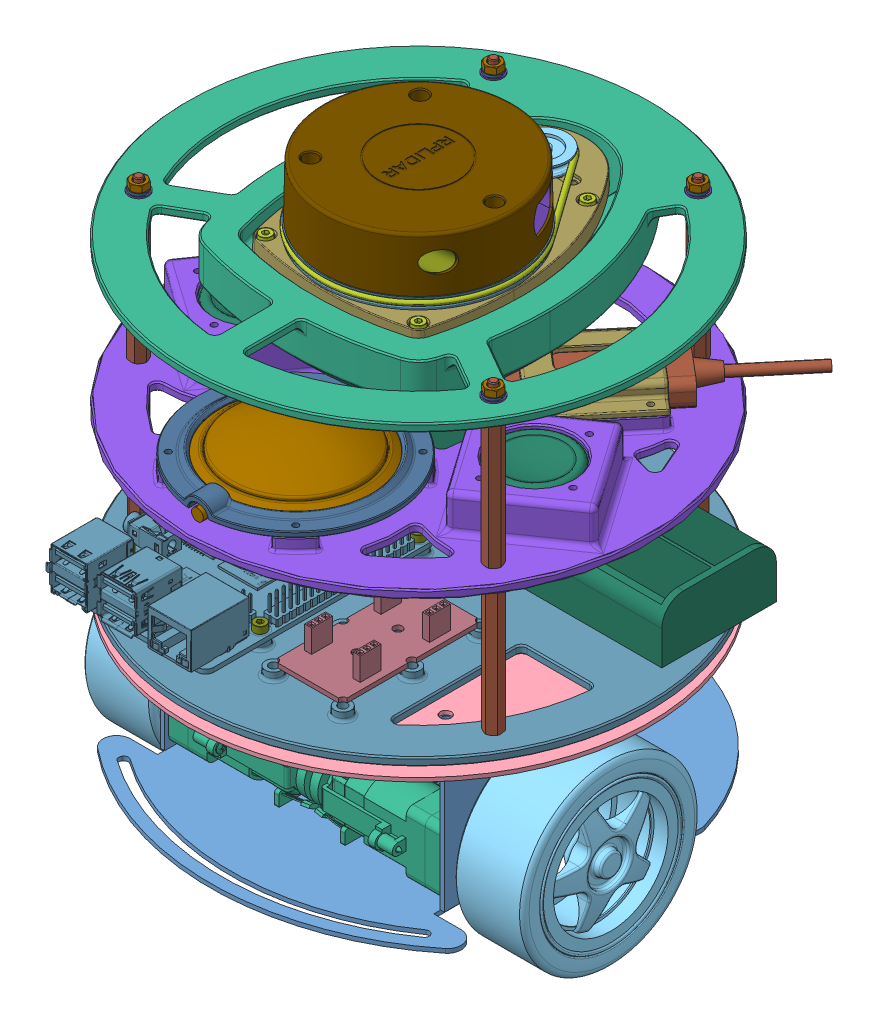
SolidWorks assembly ABOT_V2, configuration По умолчанию. Lengths in mm.
Overall size (170 211.91 174.34).
151 component instances, 52 part files, 151 mates.
Components (placement in the parent):
- LOWER_PLATE-1: LOWER_PLATE [По умолчанию] at origin size (144.85 55.5 162.2)
- CASTER_WHEEL_CASE-1: CASTER_WHEEL_CASE [Default] at (0 -11 -78) size (48.4 16.5 32.2)
- CASTER_WHEEL_BALL-1: CASTER_WHEEL_BALL [Default] at (0 -11 -78) size (14 14 14)
- UPPER_PLATE-1: UPPER_PLATE [Default] at (0 55.5 -10) x (0 0 -1) z (0 1 0) size (169.5 169.5 1.4)
- WHEEL_D65_W26-1: WHEEL_D65_W26 [Predeterminado] at (68 14.5 0) x (1 0 0) z (0 -1 0) size (29 65 65)
- WHEEL_D65_W26-2: WHEEL_D65_W26 [Predeterminado] at (-68 14.5 0) x (-1 0 0) z (0 1 0) size (29 65 65)
- TT_ANGLE_MOTOR_WITH_ENCODER-3: TT_ANGLE_MOTOR_WITH_ENCODER [По умолчанию] at (43.5 16.5594 11.0834) x (0 0 -1) z (-1 0 0) size (47.9 25.5 58.37)
- TT_ANGLE_MOTOR_WITH_ENCODER-4: TT_ANGLE_MOTOR_WITH_ENCODER [По умолчанию] at (-43.5 12.4406 11.0834) x (0 0 -1) z (1 0 0) size (47.9 25.5 58.37)
- SCREWS_ASSM_1-1: SCREWS_ASSM_1 [По умолчанию] at (64.9952 52 27.525) x (-0.813242 0 0.581925) z (-0.581925 0 -0.813242) size (7.78 19 7.78)
  - DIN_912_M3_16H-1: DIN_912_M3_16H [По умолчанию] x (0 1 0) z (0.698971 0 0.71515) size (19 5.5 5.5)
  - DIN_125_M3_WASHER_NORMAL-3: DIN_125_M3_WASHER_NORMAL [Default] at (0 3.5 0) x (0 0 1) z (0 -1 0) size (7 7 0.5)
  - DIN_934_M3_HEX_NUT-1: DIN_934_M3_HEX_NUT [По умолчанию] at (0 8.6 0) x (-0.959906 0 0.280322) z (0 -1 0) size (5.5 6.35 2.4)
  - DIN_125_M3_WASHER_NORMAL-2: DIN_125_M3_WASHER_NORMAL [Default] at (0 5.4 0) x (1 0 0) z (0 -1 0) size (7 7 0.5)
  - DIN_127_M3_SPRING_WASHER-1: DIN_127_M3_SPRING_WASHER [Default] at (0 6.2 0) x (1 0 0) z (0 -1 0) size (6.19 6.2 0.8)
- SCREWS_ASSM_1-2: SCREWS_ASSM_1 [По умолчанию] at (37.525 52 -74.9952) x (-0.954973 0 -0.296694) z (0.296694 0 -0.954973) size (7.78 19 7.78)
  - DIN_912_M3_16H-1: DIN_912_M3_16H [По умолчанию] x (0 1 0) z (0.698971 0 0.71515) size (19 5.5 5.5)
  - DIN_125_M3_WASHER_NORMAL-3: DIN_125_M3_WASHER_NORMAL [Default] at (0 3.5 0) x (0 0 1) z (0 -1 0) size (7 7 0.5)
  - DIN_934_M3_HEX_NUT-1: DIN_934_M3_HEX_NUT [По умолчанию] at (0 8.6 0) x (-0.959906 0 0.280322) z (0 -1 0) size (5.5 6.35 2.4)
  - DIN_125_M3_WASHER_NORMAL-2: DIN_125_M3_WASHER_NORMAL [Default] at (0 5.4 0) x (1 0 0) z (0 -1 0) size (7 7 0.5)
  - DIN_127_M3_SPRING_WASHER-1: DIN_127_M3_SPRING_WASHER [Default] at (0 6.2 0) x (1 0 0) z (0 -1 0) size (6.19 6.2 0.8)
- SCREWS_ASSM_1-3: SCREWS_ASSM_1 [По умолчанию] at (-37.525 52 -74.9952) size (7.78 19 7.78)
  - DIN_912_M3_16H-1: DIN_912_M3_16H [По умолчанию] x (0 1 0) z (0.698971 0 0.71515) size (19 5.5 5.5)
  - DIN_125_M3_WASHER_NORMAL-3: DIN_125_M3_WASHER_NORMAL [Default] at (0 3.5 0) x (0 0 1) z (0 -1 0) size (7 7 0.5)
  - DIN_934_M3_HEX_NUT-1: DIN_934_M3_HEX_NUT [По умолчанию] at (0 8.6 0) x (-0.959906 0 0.280322) z (0 -1 0) size (5.5 6.35 2.4)
  - DIN_125_M3_WASHER_NORMAL-2: DIN_125_M3_WASHER_NORMAL [Default] at (0 5.4 0) x (1 0 0) z (0 -1 0) size (7 7 0.5)
  - DIN_127_M3_SPRING_WASHER-1: DIN_127_M3_SPRING_WASHER [Default] at (0 6.2 0) x (1 0 0) z (0 -1 0) size (6.19 6.2 0.8)
- SCREWS_ASSM_1-4: SCREWS_ASSM_1 [По умолчанию] at (-64.9952 52 27.525) size (7.78 19 7.78)
  - DIN_912_M3_16H-1: DIN_912_M3_16H [По умолчанию] x (0 1 0) z (0.698971 0 0.71515) size (19 5.5 5.5)
  - DIN_125_M3_WASHER_NORMAL-3: DIN_125_M3_WASHER_NORMAL [Default] at (0 3.5 0) x (0 0 1) z (0 -1 0) size (7 7 0.5)
  - DIN_934_M3_HEX_NUT-1: DIN_934_M3_HEX_NUT [По умолчанию] at (0 8.6 0) x (-0.959906 0 0.280322) z (0 -1 0) size (5.5 6.35 2.4)
  - DIN_125_M3_WASHER_NORMAL-2: DIN_125_M3_WASHER_NORMAL [Default] at (0 5.4 0) x (1 0 0) z (0 -1 0) size (7 7 0.5)
  - DIN_127_M3_SPRING_WASHER-1: DIN_127_M3_SPRING_WASHER [Default] at (0 6.2 0) x (1 0 0) z (0 -1 0) size (6.19 6.2 0.8)
- STANDOFF_M3_50-13: STANDOFF_M3_50 [По умолчанию] at (-37.525 63.4 -74.9952) x (0 1 0) z (0.899685 0 0.436539) size (58 6.35 5.5)
- STANDOFF_M3_50-10: STANDOFF_M3_50 [По умолчанию] at (-64.9952 63.4 27.525) x (0 1 0) z (-0.609784 0 0.792568) size (58 6.35 5.5)
- STANDOFF_M3_50-11: STANDOFF_M3_50 [По умолчанию] at (64.9952 63.4 27.525) x (0 1 0) z (0.551155 0 0.834403) size (58 6.35 5.5)
- STANDOFF_M3_50-12: STANDOFF_M3_50 [По умолчанию] at (37.525 63.4 -74.9952) x (0 1 0) z (-0.976661 0 -0.214789) size (58 6.35 5.5)
- LIDAR-2: LIDAR [По умолчанию] at (0 184.9 -10) x (0 0 -1) z (1 0 0) size (102.81 52.61 71.78)
  - 1-1: 1 [По умолчанию] at (0 -17 0) size (96.74 12.71 70.28)
  - 2-1: 2 [По умолчанию] at (0 -15 0) x (1 0 0) z (0 -1 0) size (47 47 7.01)
  - 3-1: 3 [По умолчанию] at (0 -13 0) x (0.00451 0 -0.99999) z (0.99999 0 0.00451) size (70.79 21.41 70.79)
  - 4-1: 4 [По умолчанию] at (-25.1552 0 -6.8741) x (0.990886 0 -0.134705) z (0.134705 0 0.990886) size (6.5 6.5 21.2)
  - 5-1: 5 [По умолчанию] at (0 -9 0) x (-0.99999 0 -0.00451) z (0.00451 0 -0.99999) size (15.26 18.52 21.56)
  - 6-1: 6 [По умолчанию] at (0 -9 0) x (-0.99999 0 -0.00451) z (0.00451 0 -0.99999) size (22.09 18.86 24.76)
  - 7-1: 7 [По умолчанию] at (0 9 0) x (0.99999 0 0.00451) z (0.00451 0 -0.99999) size (70 19.51 70)
  - 8-1: 8 [По умолчанию] at (0 -26 0) x (0.987093 0 -0.160146) z (0.160146 0 0.987093) size (25 1.2 25)
  - 9-1: 9 [По умолчанию] at (0 -27 0) size (55.5 1 57)
  - 10-1: 10 [По умолчанию] at (0 -28 0) size (59.96 11.11 60.96)
  - 11-1: 11 [По умолчанию] at (45.5 -36.5 0) x (0 0 -1) z (1 0 0) size (32 30.21 32.01)
  - 12-1: 12 [По умолчанию] at (45.5 -14.5 0) x (0.135455 0 -0.990784) z (0.990784 0 0.135455) size (18 5.5 18)
  - 13-1: 13 [По умолчанию] at (16.948 0 11.5766) x (0.136926 0.990581 0.000618) z (-0.00451 0 0.99999) size (14 14 11.5)
  - 14-1: 14 [По умолчанию] at (0 -12.5 0) x (1 0 0) z (0 -1 0) size (90.89 71.78 2)
  - 15-1: 15 [По умолчанию] at (24.11 -29.4 0) x (0 0 -1) z (0 -1 0) size (10.15 4.2 4.7)
  - 16-1: 16 [По умолчанию] at (45.5 -40.1 0) x (-0.441218 0 -0.8974) z (0.8974 0 -0.441218) size (32 1.6 32)
  - 17-1: 17 [По умолчанию] at (32.56 -41.8 0) x (0 0 1) z (0 -1 0) size (8.9 5.2 3.4)
  - 19-1: 19 [По умолчанию] at (0 -36 0) x (1 0 0) z (0 0 -1) size (80.7 4.7 70)
  - 20-1: 20 [По умолчанию] at (0 -37.6 27.1) x (0 -1 0) z (1 0 0) size (8.2 5 20)
  - 22-1: 22 [По умолчанию] at (17.68 -37.7 0) x (0 0 1) z (1 0 0) size (8.8 4.7 4.36)
- PRINT_PLATE_0-1: PRINT_PLATE_0 [Default] at (0 60.4 -10) x (0 0 -1) z (0 1 0) size (170 170 6)
- COMMON_18650_BATTERY_HOLDER_DUMMY-1: COMMON_18650_BATTERY_HOLDER_DUMMY [Default] at (38.075 63.4 -43.9612) x (0 0 -1) z (1 0 0) size (42 20.5 76.3)
- COMMON_18650_BATTERY_HOLDER_DUMMY-2: COMMON_18650_BATTERY_HOLDER_DUMMY [Default] at (-38.075 63.4 -43.9612) x (0 0 -1) z (1 0 0) size (42 20.5 76.3)
- SCREWS_ASSM_2-1: SCREWS_ASSM_2 [Default] at (-5 70.48 43) x (0 -1 0) z (-0.89919 0 0.437559) size (13.2 7.37 7.37)
  - DIN_912_M2.5_10H-1: DIN_912_M2.5_10H [По умолчанию] at origin size (12.5 4.5 4.5)
  - DIN_125_M2.5_WASHER_NORMAL-1: DIN_125_M2.5_WASHER_NORMAL [Default] at (10.6 0 0) x (0 -0.264678 0.964337) z (-1 0 0) size (6 6 0.5)
  - DIN_934_M2.5_HEX_NUT-1: DIN_934_M2.5_HEX_NUT [По умолчанию] at (13.2 0 0) x (0 0 1) z (-1 0 0) size (5 5.77 2)
  - DIN_127_M2.5_SPRING_WASHER-1: DIN_127_M2.5_SPRING_WASHER [Default] at (11.2 0 0) x (0 0 1) z (-1 0 0) size (5.09 5.1 0.6)
- SCREWS_ASSM_2-2: SCREWS_ASSM_2 [Default] at (-54 70.48 43) x (0 -1 0) z (-0.949497 0 -0.313777) size (13.2 7.37 7.37)
  - DIN_912_M2.5_10H-1: DIN_912_M2.5_10H [По умолчанию] at origin size (12.5 4.5 4.5)
  - DIN_125_M2.5_WASHER_NORMAL-1: DIN_125_M2.5_WASHER_NORMAL [Default] at (10.6 0 0) x (0 -0.264678 0.964337) z (-1 0 0) size (6 6 0.5)
  - DIN_934_M2.5_HEX_NUT-1: DIN_934_M2.5_HEX_NUT [По умолчанию] at (13.2 0 0) x (0 0 1) z (-1 0 0) size (5 5.77 2)
  - DIN_127_M2.5_SPRING_WASHER-1: DIN_127_M2.5_SPRING_WASHER [Default] at (11.2 0 0) x (0 0 1) z (-1 0 0) size (5.09 5.1 0.6)
- SCREWS_ASSM_2-3: SCREWS_ASSM_2 [Default] at (-54 70.48 -15) x (0 -1 0) z (-0.237105 0 0.971484) size (13.2 7.37 7.37)
  - DIN_912_M2.5_10H-1: DIN_912_M2.5_10H [По умолчанию] at origin size (12.5 4.5 4.5)
  - DIN_125_M2.5_WASHER_NORMAL-1: DIN_125_M2.5_WASHER_NORMAL [Default] at (10.6 0 0) x (0 -0.264678 0.964337) z (-1 0 0) size (6 6 0.5)
  - DIN_934_M2.5_HEX_NUT-1: DIN_934_M2.5_HEX_NUT [По умолчанию] at (13.2 0 0) x (0 0 1) z (-1 0 0) size (5 5.77 2)
  - DIN_127_M2.5_SPRING_WASHER-1: DIN_127_M2.5_SPRING_WASHER [Default] at (11.2 0 0) x (0 0 1) z (-1 0 0) size (5.09 5.1 0.6)
- SCREWS_ASSM_2-4: SCREWS_ASSM_2 [Default] at (-5 70.48 -15) x (0 -1 0) z (-0.388057 0 0.921636) size (13.2 7.37 7.37)
  - DIN_912_M2.5_10H-1: DIN_912_M2.5_10H [По умолчанию] at origin size (12.5 4.5 4.5)
  - DIN_125_M2.5_WASHER_NORMAL-1: DIN_125_M2.5_WASHER_NORMAL [Default] at (10.6 0 0) x (0 -0.264678 0.964337) z (-1 0 0) size (6 6 0.5)
  - DIN_934_M2.5_HEX_NUT-1: DIN_934_M2.5_HEX_NUT [По умолчанию] at (13.2 0 0) x (0 0 1) z (-1 0 0) size (5 5.77 2)
  - DIN_127_M2.5_SPRING_WASHER-1: DIN_127_M2.5_SPRING_WASHER [Default] at (11.2 0 0) x (0 0 1) z (-1 0 0) size (5.09 5.1 0.6)
- SCREWS_ASSM_3-1: SCREWS_ASSM_3 [Default] at (-38.075 66 -33.4612) x (0 -1 0) z (0 0 1) size (8 6.6 6.6)
  - DIN_125_M2_WASHER_NORMAL-1: DIN_125_M2_WASHER_NORMAL [Default] at (5.9 0 0) x (0 -0.405412 0.914134) z (-1 0 0) size (5 5 0.3)
  - DIN_127_M2_SPRING_WASHER-1: DIN_127_M2_SPRING_WASHER [Default] at (6.4 0 0) x (0 0 1) z (-1 0 0) size (4.39 4.4 0.5)
  - DIN_912_M2_6H-1: DIN_912_M2_6H [По умолчанию] at origin size (8 3.8 3.8)
  - DIN_934_M2_HEX_NUT-1: DIN_934_M2_HEX_NUT [По умолчанию] at (8 0 0) x (0 0.297102 0.954846) z (-1 0 0) size (4 4.62 1.6)
- SCREWS_ASSM_3-2: SCREWS_ASSM_3 [Default] at (38.075 66 -33.4612) x (0 -1 0) z (0 0 1) size (8 6.6 6.6)
  - DIN_125_M2_WASHER_NORMAL-1: DIN_125_M2_WASHER_NORMAL [Default] at (5.9 0 0) x (0 -0.405412 0.914134) z (-1 0 0) size (5 5 0.3)
  - DIN_127_M2_SPRING_WASHER-1: DIN_127_M2_SPRING_WASHER [Default] at (6.4 0 0) x (0 0 1) z (-1 0 0) size (4.39 4.4 0.5)
  - DIN_912_M2_6H-1: DIN_912_M2_6H [По умолчанию] at origin size (8 3.8 3.8)
  - DIN_934_M2_HEX_NUT-1: DIN_934_M2_HEX_NUT [По умолчанию] at (8 0 0) x (0 0.297102 0.954846) z (-1 0 0) size (4 4.62 1.6)
- SCREWS_ASSM_3-3: SCREWS_ASSM_3 [Default] at (38.075 66 -54.4612) x (0 -1 0) z (-0.226683 0 0.973969) size (8 6.6 6.6)
  - DIN_125_M2_WASHER_NORMAL-1: DIN_125_M2_WASHER_NORMAL [Default] at (5.9 0 0) x (0 -0.405412 0.914134) z (-1 0 0) size (5 5 0.3)
  - DIN_127_M2_SPRING_WASHER-1: DIN_127_M2_SPRING_WASHER [Default] at (6.4 0 0) x (0 0 1) z (-1 0 0) size (4.39 4.4 0.5)
  - DIN_912_M2_6H-1: DIN_912_M2_6H [По умолчанию] at origin size (8 3.8 3.8)
  - DIN_934_M2_HEX_NUT-1: DIN_934_M2_HEX_NUT [По умолчанию] at (8 0 0) x (0 0.297102 0.954846) z (-1 0 0) size (4 4.62 1.6)
- SCREWS_ASSM_3-4: SCREWS_ASSM_3 [Default] at (-38.075 66 -54.4612) x (0 -1 0) z (0 0 1) size (8 6.6 6.6)
  - DIN_125_M2_WASHER_NORMAL-1: DIN_125_M2_WASHER_NORMAL [Default] at (5.9 0 0) x (0 -0.405412 0.914134) z (-1 0 0) size (5 5 0.3)
  - DIN_127_M2_SPRING_WASHER-1: DIN_127_M2_SPRING_WASHER [Default] at (6.4 0 0) x (0 0 1) z (-1 0 0) size (4.39 4.4 0.5)
  - DIN_912_M2_6H-1: DIN_912_M2_6H [По умолчанию] at origin size (8 3.8 3.8)
  - DIN_934_M2_HEX_NUT-1: DIN_934_M2_HEX_NUT [По умолчанию] at (8 0 0) x (0 0.297102 0.954846) z (-1 0 0) size (4 4.62 1.6)
- PRINT_PLATE_1-1: PRINT_PLATE_1 [Default] at (0 166.4 -10) x (0 0 -1) z (0 1 0) size (170 170 20.5)
- SCREWS_ASSM_4-1: SCREWS_ASSM_4 [Default] at (-20 169.9 -52) x (0 -1 0) z (0.489917 0 0.871769) size (27.5 6 6)
  - DIN_912_M2.5_25H-1: DIN_912_M2.5_25H [По умолчанию] at origin size (27.5 4.5 4.5)
  - DIN_125_M2.5_WASHER_NORMAL-1: DIN_125_M2.5_WASHER_NORMAL [Default] at (23.1 0 0) x (0 0 1) z (-1 0 0) size (6 6 0.5)
  - DIN_127_M2.5_SPRING_WASHER-1: DIN_127_M2.5_SPRING_WASHER [Default] at (23.7 0 0) x (0 0 1) z (-1 0 0) size (5.09 5.1 0.6)
  - DIN_934_M2.5_HEX_NUT-1: DIN_934_M2.5_HEX_NUT [По умолчанию] at (25.7 0 0) x (0 0 1) z (-1 0 0) size (5 5.77 2)
- SCREWS_ASSM_4-2: SCREWS_ASSM_4 [Default] at (20 169.9 -52) x (0 -1 0) z (0.489917 0 0.871769) size (27.5 6 6)
  - DIN_912_M2.5_25H-1: DIN_912_M2.5_25H [По умолчанию] at origin size (27.5 4.5 4.5)
  - DIN_125_M2.5_WASHER_NORMAL-1: DIN_125_M2.5_WASHER_NORMAL [Default] at (23.1 0 0) x (0 0 1) z (-1 0 0) size (6 6 0.5)
  - DIN_127_M2.5_SPRING_WASHER-1: DIN_127_M2.5_SPRING_WASHER [Default] at (23.7 0 0) x (0 0 1) z (-1 0 0) size (5.09 5.1 0.6)
  - DIN_934_M2.5_HEX_NUT-1: DIN_934_M2.5_HEX_NUT [По умолчанию] at (25.7 0 0) x (0 0 1) z (-1 0 0) size (5 5.77 2)
- SCREWS_ASSM_4-3: SCREWS_ASSM_4 [Default] at (28 169.9 18) x (0 -1 0) z (0.489917 0 0.871769) size (27.5 6 6)
  - DIN_912_M2.5_25H-1: DIN_912_M2.5_25H [По умолчанию] at origin size (27.5 4.5 4.5)
  - DIN_125_M2.5_WASHER_NORMAL-1: DIN_125_M2.5_WASHER_NORMAL [Default] at (23.1 0 0) x (0 0 1) z (-1 0 0) size (6 6 0.5)
  - DIN_127_M2.5_SPRING_WASHER-1: DIN_127_M2.5_SPRING_WASHER [Default] at (23.7 0 0) x (0 0 1) z (-1 0 0) size (5.09 5.1 0.6)
  - DIN_934_M2.5_HEX_NUT-1: DIN_934_M2.5_HEX_NUT [По умолчанию] at (25.7 0 0) x (0 0 1) z (-1 0 0) size (5 5.77 2)
- SCREWS_ASSM_4-4: SCREWS_ASSM_4 [Default] at (-28 169.9 18) x (0 -1 0) z (0.489917 0 0.871769) size (27.5 6 6)
  - DIN_912_M2.5_25H-1: DIN_912_M2.5_25H [По умолчанию] at origin size (27.5 4.5 4.5)
  - DIN_125_M2.5_WASHER_NORMAL-1: DIN_125_M2.5_WASHER_NORMAL [Default] at (23.1 0 0) x (0 0 1) z (-1 0 0) size (6 6 0.5)
  - DIN_127_M2.5_SPRING_WASHER-1: DIN_127_M2.5_SPRING_WASHER [Default] at (23.7 0 0) x (0 0 1) z (-1 0 0) size (5.09 5.1 0.6)
  - DIN_934_M2.5_HEX_NUT-1: DIN_934_M2.5_HEX_NUT [По умолчанию] at (25.7 0 0) x (0 0 1) z (-1 0 0) size (5 5.77 2)
- SCREWS_ASSM_5-1: SCREWS_ASSM_5 [Default] at (37.525 173.1 -74.9952) x (1 0 0) z (0 -1 0) size (8.46 8.46 3.7)
  - DIN_934_M3_HEX_NUT-1: DIN_934_M3_HEX_NUT [По умолчанию] at origin size (5.5 6.35 2.4)
  - DIN_125_M3_WASHER_NORMAL-1: DIN_125_M3_WASHER_NORMAL [Default] at (0 0 3.2) x (0.971662 0.236376 0) z (0 0 1) size (7 7 0.5)
  - DIN_127_M3_SPRING_WASHER-1: DIN_127_M3_SPRING_WASHER [Default] at (0 0 2.4) size (6.19 6.2 0.8)
- SCREWS_ASSM_5-2: SCREWS_ASSM_5 [Default] at (-37.525 173.1 -74.9952) x (1 0 0) z (0 -1 0) size (8.46 8.46 3.7)
  - DIN_934_M3_HEX_NUT-1: DIN_934_M3_HEX_NUT [По умолчанию] at origin size (5.5 6.35 2.4)
  - DIN_125_M3_WASHER_NORMAL-1: DIN_125_M3_WASHER_NORMAL [Default] at (0 0 3.2) x (0.971662 0.236376 0) z (0 0 1) size (7 7 0.5)
  - DIN_127_M3_SPRING_WASHER-1: DIN_127_M3_SPRING_WASHER [Default] at (0 0 2.4) size (6.19 6.2 0.8)
- SCREWS_ASSM_5-3: SCREWS_ASSM_5 [Default] at (-64.9952 173.1 27.525) x (1 0 0) z (0 -1 0) size (8.46 8.46 3.7)
  - DIN_934_M3_HEX_NUT-1: DIN_934_M3_HEX_NUT [По умолчанию] at origin size (5.5 6.35 2.4)
  - DIN_125_M3_WASHER_NORMAL-1: DIN_125_M3_WASHER_NORMAL [Default] at (0 0 3.2) x (0.971662 0.236376 0) z (0 0 1) size (7 7 0.5)
  - DIN_127_M3_SPRING_WASHER-1: DIN_127_M3_SPRING_WASHER [Default] at (0 0 2.4) size (6.19 6.2 0.8)
- SCREWS_ASSM_5-4: SCREWS_ASSM_5 [Default] at (64.9952 173.1 27.525) x (1 0 0) z (0 -1 0) size (8.46 8.46 3.7)
  - DIN_934_M3_HEX_NUT-1: DIN_934_M3_HEX_NUT [По умолчанию] at origin size (5.5 6.35 2.4)
  - DIN_125_M3_WASHER_NORMAL-1: DIN_125_M3_WASHER_NORMAL [Default] at (0 0 3.2) x (0.971662 0.236376 0) z (0 0 1) size (7 7 0.5)
  - DIN_127_M3_SPRING_WASHER-1: DIN_127_M3_SPRING_WASHER [Default] at (0 0 2.4) size (6.19 6.2 0.8)
- PRINT_PLATE_SOUND_0-1: PRINT_PLATE_SOUND_0 [Default] at (0 113.4 -10) x (0 0 -1) z (0 1 0) size (170 170 20)
- TABLETOP_MICROPHONE_ATR4697-1: TABLETOP_MICROPHONE_ATR4697 [Default] at (0 116.4 35) x (0 0 1) z (-1 0 0) size (66 15 60)
- PRINT_MIC_CAP-1: PRINT_MIC_CAP [Default] at (0 120.9 35) size (72 5.58 72)
- CREATIVE_SOUND_BLASTER_PLAY_3-1: CREATIVE_SOUND_BLASTER_PLAY_3 [Default] at (45.895 121.1 -64.6956) x (0.642788 0 -0.766044) z (0.766044 0 0.642788) size (86.8 9.4 22)
- PRINT_SOUND_CARD_CAP-1: PRINT_SOUND_CARD_CAP [Default] at (28.9254 121.1 -44.472) x (0.642788 0 -0.766044) z (0.766044 0 0.642788) size (38 6.7 38)
- STANDOFF_M3_50-6: STANDOFF_M3_50 [По умолчанию] at (37.525 116.4 -74.9952) x (0 1 0) z (-0.819797 0 -0.572654) size (58 6.35 5.5)
- STANDOFF_M3_50-7: STANDOFF_M3_50 [По умолчанию] at (64.9952 116.4 27.525) x (0 1 0) z (0.788533 0 0.614992) size (58 6.35 5.5)
- STANDOFF_M3_50-8: STANDOFF_M3_50 [По умолчанию] at (-64.9952 116.4 27.525) x (0 1 0) z (-0.908998 0 0.416801) size (58 6.35 5.5)
- STANDOFF_M3_50-9: STANDOFF_M3_50 [По умолчанию] at (-37.525 116.4 -74.9952) x (0 1 0) z (0.784935 0 0.619578) size (58 6.35 5.5)
- TROYKA_PAD_X2_DUMMY-1: TROYKA_PAD_X2_DUMMY [Default] at (20 68 25) x (0 0 1) z (-1 0 0) size (50.8 11.6 25.4)
- RP_4_DUMMY-1: RP_4_DUMMY [Default] at (-29.5 67.19 24) x (0 0 1) z (-1 0 0) size (88.99 19.9 58.4)
- VECO_32KC08_1-1: VECO_32KC08_1 [Default] at (51.7024 127.3 -0.8835) x (0.819152 0 -0.573576) z (0.573576 0 0.819152) size (32 14.7 32)
- VECO_32KC08_1-2: VECO_32KC08_1 [Default] at (-51.7024 127.3 -0.8835) x (0.819152 0 0.573576) z (-0.573576 0 0.819152) size (32 14.7 32)
- TROYKA_AMPLIFIER_D-1: TROYKA_AMPLIFIER_D [По умолчанию] at (-46.8176 131.8525 -46.0374) x (0.642788 0 0.766044) z (0 1 0) size (25.4 25.4 18.38)
Mates (geometry in assembly coordinates):
- Концентричный17: concentric anti-aligned: cylinder of LOWER_PLATE-1 through (0 1.5 -78) axis (0 -1 0) radius 16; cylinder of CASTER_WHEEL_CASE-1 through (0 -14 -78) axis (0 1 0) radius 16.1
- Концентричный18: concentric aligned: cylinder of LOWER_PLATE-1 through (20 0 -78) axis (0 1 0) radius 2.05; cylinder of CASTER_WHEEL_CASE-1 through (20 -14 -78) axis (0 1 0) radius 2
- Совпадение15: coincident anti-aligned: plane of LOWER_PLATE-1 through (0 1.5 0) normal (0 1 0); plane of CASTER_WHEEL_CASE-1 through (0 1.5 -78) normal (0 -1 0)
- Совпадение16: coordinate: point of CASTER_WHEEL_CASE-1; point of CASTER_WHEEL_BALL-1
- Концентричный22: concentric aligned: cylinder of LOWER_PLATE-1 through (-45 55.5 25) axis (0 -1 0) radius 1.5; cylinder of UPPER_PLATE-1 through (-45 56.9 25) axis (0 -1 0) radius 2
- Концентричный23: concentric aligned: cylinder of LOWER_PLATE-1 through (45 55.5 -25) axis (0 -1 0) radius 1.5; cylinder of UPPER_PLATE-1 through (45 56.9 -25) axis (0 -1 0) radius 2
- Совпадение30: coincident anti-aligned: plane of LOWER_PLATE-1 through (0 55.5 0) normal (0 1 0); plane of UPPER_PLATE-1 through (0 55.5 -10) normal (0 -1 0)
- Совпадение35: coincident anti-aligned: plane of LOWER_PLATE-1 through (52 55 0) normal (1 0 0); plane of WHEEL_D65_W26-1 through (52 14.5 0) normal (-1 0 0)
- Совпадение36: coincident anti-aligned: plane of LOWER_PLATE-1 through (-52 55 0) normal (-1 0 0); plane of WHEEL_D65_W26-2 through (-52 14.5 0) normal (1 0 0)
- Concentric1: concentric anti-aligned: cylinder of LOWER_PLATE-1 through (54 14.5 0) axis (-1 0 0) radius 4; cylinder of TT_ANGLE_MOTOR_WITH_ENCODER-4 through (-59.3 14.5 0) axis (1 0 0) radius 2.7
- Concentric2: concentric aligned: cylinder of LOWER_PLATE-1 through (-72.4232 14.5 11.4) axis (1 0 0) radius 2; cylinder of TT_ANGLE_MOTOR_WITH_ENCODER-4 through (-52.5 14.5 11.4) axis (1 0 0) radius 2
- Coincident1: coincident anti-aligned: plane of LOWER_PLATE-1 through (-50.5 55 -32.5) normal (1 0 0); plane of TT_ANGLE_MOTOR_WITH_ENCODER-4 through (-50.5 23.5 -8.5) normal (-1 0 0)
- Concentric3: concentric aligned: cylinder of LOWER_PLATE-1 through (54 14.5 0) axis (-1 0 0) radius 4; cylinder of TT_ANGLE_MOTOR_WITH_ENCODER-3 through (59.3 14.5 0) axis (-1 0 0) radius 2.7
- Concentric4: concentric anti-aligned: cylinder of LOWER_PLATE-1 through (-72.4232 14.5 11.4) axis (1 0 0) radius 2; cylinder of TT_ANGLE_MOTOR_WITH_ENCODER-3 through (52.5 14.5 11.4) axis (-1 0 0) radius 2
- Coincident2: coincident anti-aligned: plane of LOWER_PLATE-1 through (50.5 55 -32.5) normal (-1 0 0); plane of TT_ANGLE_MOTOR_WITH_ENCODER-3 through (50.5 5.5 -8.5) normal (1 0 0)
- Concentric5: concentric anti-aligned: cylinder of WHEEL_D65_W26-2 through (-68.8553 14.5 0) axis (-1 0 0) radius 4; cylinder of TT_ANGLE_MOTOR_WITH_ENCODER-4 through (-59.3 14.5 0) axis (1 0 0) radius 2.7
- Concentric6: concentric anti-aligned: cylinder of WHEEL_D65_W26-1 through (68.8553 14.5 0) axis (1 0 0) radius 4; cylinder of TT_ANGLE_MOTOR_WITH_ENCODER-3 through (59.3 14.5 0) axis (-1 0 0) radius 2.7
- Concentric21: concentric anti-aligned: cylinder of SCREWS_ASSM_1-1/DIN_912_M3_16H-1 through (64.9952 52 27.525) axis (0 -1 0) radius 1.5; circle of UPPER_PLATE-1
- Coincident12: coincident anti-aligned: plane of UPPER_PLATE-1 through (0 55.5 -10) normal (0 -1 0); plane of SCREWS_ASSM_1-1/DIN_125_M3_WASHER_NORMAL-3 through (64.9952 55.5 27.525) normal (0 1 0)
- Concentric22: concentric anti-aligned: cylinder of SCREWS_ASSM_1-2/DIN_912_M3_16H-1 through (37.525 52 -74.9952) axis (0 -1 0) radius 1.5; circle of UPPER_PLATE-1
- Coincident14: coincident anti-aligned: plane of UPPER_PLATE-1 through (0 55.5 -10) normal (0 -1 0); plane of SCREWS_ASSM_1-2/DIN_125_M3_WASHER_NORMAL-3 through (37.525 55.5 -74.9952) normal (0 1 0)
- Concentric23: concentric anti-aligned: circle of UPPER_PLATE-1; cylinder of SCREWS_ASSM_1-4/DIN_912_M3_16H-1 through (-64.9952 52 27.525) axis (0 -1 0) radius 1.5
- Concentric24: concentric anti-aligned: cylinder of SCREWS_ASSM_1-3/DIN_912_M3_16H-1 through (-37.525 52 -74.9952) axis (0 -1 0) radius 1.5; circle of UPPER_PLATE-1
- Coincident15: coincident anti-aligned: plane of UPPER_PLATE-1 through (0 55.5 -10) normal (0 -1 0); plane of SCREWS_ASSM_1-3/DIN_125_M3_WASHER_NORMAL-3 through (-37.525 55.5 -74.9952) normal (0 1 0)
- Coincident16: coincident anti-aligned: plane of UPPER_PLATE-1 through (0 55.5 -10) normal (0 -1 0); plane of SCREWS_ASSM_1-4/DIN_125_M3_WASHER_NORMAL-3 through (-64.9952 55.5 27.525) normal (0 1 0)
- Concentric34: concentric aligned: cylinder of ? through (-64.9952 136.4 27.525) axis (0 -1 0) radius 1.5; cylinder of ? through (-64.9952 119.4 27.525) axis (0 -1 0) radius 1.6
- Coincident26: coincident anti-aligned: plane of ? through (0 119.4 -10) normal (0 1 0); plane of LIDAR-2/1-1 through (62.2833 119.4 -10) normal (0 -1 0)
- Concentric35: concentric aligned: cylinder of ? through (20 119.4 -52) axis (0 -1 0) radius 1.5; cylinder of LIDAR-2/1-1 through (20 122.7 -52) axis (0 -1 0) radius 1.5
- Concentric36: concentric aligned: cylinder of ? through (28 119.4 18) axis (0 -1 0) radius 1.5; cylinder of LIDAR-2/1-1 through (28 122.7 18) axis (0 -1 0) radius 1.5
- Concentric38: concentric aligned: cylinder of ? through (0 -4.1 84.5) axis (0 0 -1) radius 1.6; cylinder of ? through (0 -4.1 80) axis (0 0 -1) radius 1.6
- Concentric39: concentric aligned: cylinder of ? through (0 32.9 84.5) axis (0 0 -1) radius 1.6; cylinder of ? through (0 32.9 80) axis (0 0 -1) radius 1.6
- Coincident27: coincident anti-aligned: plane of ? through (0 14.4 79.5) normal (0 0 -1); plane of ? through (0 -8.1 79.5) normal (0 0 1)
- Concentric40: concentric anti-aligned: cylinder of ? through (0 32.9 84.5) axis (0 0 -1) radius 1.6; cylinder of ? through (0 32.9 84.5) axis (0 0 1) radius 1.5
- Coincident32: coincident anti-aligned: plane of ? through (0 32.9 81.5) normal (0 0 1); plane of ? through (0 32.9 81.5) normal (0 0 -1)
- Concentric42: concentric anti-aligned: cylinder of ? through (0 -4.1 84.5) axis (0 0 -1) radius 1.6; cylinder of ? through (0 -4.1 84.5) axis (0 0 1) radius 1.5
- Coincident33: coincident anti-aligned: plane of ? through (0 -4.1 81.5) normal (0 0 1); plane of ? through (0 -4.1 81.5) normal (0 0 -1)
- Concentric43: concentric aligned: cylinder of ? through (0 -4.1 74.6) axis (0 0 1) radius 1.5; cylinder of ? through (0 -4.1 84.5) axis (0 0 1) radius 1.5
- Concentric44: concentric aligned: cylinder of ? through (0 32.9 84.5) axis (0 0 1) radius 1.5; cylinder of ? through (0 32.9 74.6) axis (0 0 1) radius 1.5
- Tangent1: tangent aligned: cylinder of ? through (0 -8.1 -10) axis (0 1 0) radius 87; plane of ? through (0 32.9 77) normal (0 0 1)
- Tangent2: tangent aligned: cylinder of ? through (0 -8.1 -10) axis (0 1 0) radius 87; plane of ? through (0 -4.1 77) normal (0 0 1)
- Концентричный24: concentric aligned: cylinder of UPPER_PLATE-1 through (0 56.9 -10) axis (0 -1 0) radius 84.75; cylinder of PRINT_PLATE_0-1 through (0 63.4 -10) axis (0 -1 0) radius 85
- Концентричный25: concentric anti-aligned: cylinder of PRINT_PLATE_0-1 through (-54 63.4 43) axis (0 -1 0) radius 1.6; cylinder of ? through (-54 68 43) axis (0 1 0) radius 1.35
- Концентричный26: concentric anti-aligned: cylinder of PRINT_PLATE_0-1 through (-5 63.4 -15) axis (0 -1 0) radius 1.6; cylinder of ? through (-5 68 -15) axis (0 1 0) radius 1.35
- Совпадение37: coincident anti-aligned: plane of PRINT_PLATE_0-1 through (0 66.4 -10) normal (0 1 0); plane of ? through (-29.5 66.4 24) normal (0 -1 0)
- Концентричный28: concentric aligned: cylinder of SCREWS_ASSM_1-1/DIN_912_M3_16H-1 through (64.9952 52 27.525) axis (0 -1 0) radius 1.5; cylinder of PRINT_PLATE_0-1 through (64.9952 63.4 27.525) axis (0 -1 0) radius 1.6
- Концентричный29: concentric anti-aligned: cylinder of UPPER_PLATE-1 through (0 56.9 -10) axis (0 -1 0) radius 84.75; cylinder of ? through (0 60.4 -10) axis (0 1 0) radius 90
- Совпадение38: coincident anti-aligned: plane of STANDOFF_M3_50-10 through (-64.9952 63.4 27.525) normal (0 -1 0); plane of PRINT_PLATE_0-1 through (0 63.4 -10) normal (0 1 0)
- Совпадение39: coincident anti-aligned: plane of STANDOFF_M3_50-12 through (37.525 63.4 -74.9952) normal (0 -1 0); plane of PRINT_PLATE_0-1 through (0 63.4 -10) normal (0 1 0)
- Совпадение40: coincident anti-aligned: plane of STANDOFF_M3_50-13 through (-37.525 63.4 -74.9952) normal (0 -1 0); plane of PRINT_PLATE_0-1 through (0 63.4 -10) normal (0 1 0)
- Концентричный30: concentric anti-aligned: cylinder of SCREWS_ASSM_1-1/DIN_912_M3_16H-1 through (64.9952 51.9 27.525) axis (0 -1 0) radius 1.5; cylinder of ? through (64.9952 60.4 27.525) axis (0 1 0) radius 1.6
- Расстояние1: distance = 3.5 mm anti-aligned: plane of UPPER_PLATE-1 through (0 56.9 -10) normal (0 1 0); plane of ? through (0 60.4 -10) normal (0 -1 0)
- Совпадение42: coincident anti-aligned: plane of STANDOFF_M3_50-11 through (64.9952 63.4 27.525) normal (0 -1 0); plane of PRINT_PLATE_0-1 through (0 63.4 -10) normal (0 1 0)
- Совпадение43: coincident anti-aligned: plane of ? through (0 63.4 -10) normal (0 1 0); plane of PRINT_PLATE_0-1 through (0 63.4 -10) normal (0 -1 0)
- Концентричный31: concentric aligned: cylinder of PRINT_PLATE_0-1 through (-38.075 63.4 -54.4612) axis (0 -1 0) radius 1.5; cylinder of COMMON_18650_BATTERY_HOLDER_DUMMY-2 through (-38.075 83.9 -54.4612) axis (0 -1 0) radius 1.5
- Концентричный32: concentric aligned: cylinder of PRINT_PLATE_0-1 through (38.075 63.4 -54.4612) axis (0 -1 0) radius 1.5; cylinder of COMMON_18650_BATTERY_HOLDER_DUMMY-1 through (38.075 83.9 -54.4612) axis (0 -1 0) radius 1.5
- Концентричный33: concentric aligned: cylinder of PRINT_PLATE_0-1 through (38.075 63.4 -33.4612) axis (0 -1 0) radius 1.5; cylinder of COMMON_18650_BATTERY_HOLDER_DUMMY-1 through (38.075 83.9 -33.4612) axis (0 -1 0) radius 1.5
- Концентричный34: concentric aligned: cylinder of PRINT_PLATE_0-1 through (-38.075 63.4 -33.4612) axis (0 -1 0) radius 1.5; cylinder of COMMON_18650_BATTERY_HOLDER_DUMMY-2 through (-38.075 83.9 -33.4612) axis (0 -1 0) radius 1.5
- Совпадение44: coincident anti-aligned: plane of PRINT_PLATE_0-1 through (0 63.4 -10) normal (0 1 0); plane of COMMON_18650_BATTERY_HOLDER_DUMMY-1 through (38.075 63.4 -43.9612) normal (0 -1 0)
- Совпадение45: coincident anti-aligned: plane of PRINT_PLATE_0-1 through (0 63.4 -10) normal (0 1 0); plane of COMMON_18650_BATTERY_HOLDER_DUMMY-2 through (-38.075 63.4 -43.9612) normal (0 -1 0)
- Концентричный35: concentric anti-aligned: cylinder of PRINT_PLATE_0-1 through (20 63.4 17.5) axis (0 -1 0) radius 1.6; cylinder of TROYKA_PAD_X2_DUMMY-1 through (20 64.8 17.5) axis (0 1 0) radius 1.6
- Концентричный36: concentric anti-aligned: cylinder of PRINT_PLATE_0-1 through (20 63.4 32.5) axis (0 -1 0) radius 1.6; cylinder of TROYKA_PAD_X2_DUMMY-1 through (20 64.8 32.5) axis (0 1 0) radius 1.6
- Совпадение46: coincident anti-aligned: plane of PRINT_PLATE_0-1 through (0 66.4 -10) normal (0 1 0); plane of TROYKA_PAD_X2_DUMMY-1 through (20 66.4 25) normal (0 -1 0)
- Distance1: distance = 3.5 mm anti-aligned: plane of UPPER_PLATE-1 through (0 56.9 -10) normal (0 1 0); plane of PRINT_PLATE_0-1 through (0 60.4 -10) normal (0 -1 0)
- Concentric45: concentric aligned: cylinder of ? through (-5 68 43) axis (0 1 0) radius 1.35; cylinder of SCREWS_ASSM_2-1/DIN_912_M2.5_10H-1 through (-5 70.49 43) axis (0 1 0) radius 1.25
- Concentric46: concentric aligned: cylinder of ? through (-54 68 43) axis (0 1 0) radius 1.35; cylinder of SCREWS_ASSM_2-2/DIN_912_M2.5_10H-1 through (-54 70.49 43) axis (0 1 0) radius 1.25
- Concentric47: concentric aligned: cylinder of ? through (-54 68 -15) axis (0 1 0) radius 1.35; cylinder of SCREWS_ASSM_2-3/DIN_912_M2.5_10H-1 through (-54 70.5 -15) axis (0 1 0) radius 1.25
- Concentric48: concentric aligned: cylinder of ? through (-5 68 -15) axis (0 1 0) radius 1.35; cylinder of SCREWS_ASSM_2-4/DIN_912_M2.5_10H-1 through (-5 70.49 -15) axis (0 1 0) radius 1.25
- Coincident35: coincident anti-aligned: plane of ? through (-5 67.99 -15) normal (0 1 0); plane of SCREWS_ASSM_2-4/DIN_912_M2.5_10H-1 through (-5 67.99 -15) normal (0 -1 0)
- Coincident36: coincident aligned: plane of ? through (-5 67.99 43) normal (0 1 0); circle of SCREWS_ASSM_2-1/DIN_912_M2.5_10H-1
- Concentric49: concentric aligned: cylinder of ? through (-54 68 43) axis (0 1 0) radius 1.35; cylinder of SCREWS_ASSM_2-2/DIN_912_M2.5_10H-1 through (-54 70.49 43) axis (0 1 0) radius 1.25
- Coincident37: coincident anti-aligned: plane of ? through (-54 67.99 43) normal (0 1 0); plane of SCREWS_ASSM_2-2/DIN_912_M2.5_10H-1 through (-54 67.99 43) normal (0 -1 0)
- Concentric50: concentric aligned: cylinder of ? through (-54 68 -15) axis (0 1 0) radius 1.35; cylinder of SCREWS_ASSM_2-3/DIN_912_M2.5_10H-1 through (-54 70.5 -15) axis (0 1 0) radius 1.25
- Coincident38: coincident anti-aligned: plane of ? through (-29.5 68 24) normal (0 1 0); plane of SCREWS_ASSM_2-3/DIN_912_M2.5_10H-1 through (-54 68 -15) normal (0 -1 0)
- Concentric51: concentric anti-aligned: cylinder of PRINT_PLATE_0-1 through (-38.075 63.4 -33.4612) axis (0 -1 0) radius 1.5; cylinder of SCREWS_ASSM_3-1/DIN_912_M2_6H-1 through (-38.075 66 -33.4612) axis (0 1 0) radius 1
- Concentric52: concentric anti-aligned: cylinder of PRINT_PLATE_0-1 through (-38.075 63.4 -54.4612) axis (0 -1 0) radius 1.5; cylinder of SCREWS_ASSM_3-4/DIN_912_M2_6H-1 through (-38.075 66 -54.4612) axis (0 1 0) radius 1
- Concentric53: concentric anti-aligned: cylinder of PRINT_PLATE_0-1 through (38.075 63.4 -33.4612) axis (0 -1 0) radius 1.5; cylinder of SCREWS_ASSM_3-2/DIN_912_M2_6H-1 through (38.075 66 -33.4612) axis (0 1 0) radius 1
- Concentric54: concentric anti-aligned: cylinder of PRINT_PLATE_0-1 through (38.075 63.4 -54.4612) axis (0 -1 0) radius 1.5; cylinder of SCREWS_ASSM_3-3/DIN_912_M2_6H-1 through (38.075 66 -54.4612) axis (0 1 0) radius 1
- Coincident39: coincident anti-aligned: plane of PRINT_PLATE_0-1 through (0 60.4 -10) normal (0 -1 0); plane of SCREWS_ASSM_3-3/DIN_125_M2_WASHER_NORMAL-1 through (38.075 60.4 -54.4612) normal (0 1 0)
- Coincident40: coincident anti-aligned: plane of PRINT_PLATE_0-1 through (0 60.4 -10) normal (0 -1 0); plane of SCREWS_ASSM_3-4/DIN_125_M2_WASHER_NORMAL-1 through (-38.075 60.4 -54.4612) normal (0 1 0)
- Coincident41: coincident anti-aligned: plane of PRINT_PLATE_0-1 through (0 60.4 -10) normal (0 -1 0); plane of SCREWS_ASSM_3-2/DIN_125_M2_WASHER_NORMAL-1 through (38.075 60.4 -33.4612) normal (0 1 0)
- Coincident42: coincident anti-aligned: plane of PRINT_PLATE_0-1 through (0 60.4 -10) normal (0 -1 0); plane of SCREWS_ASSM_3-1/DIN_125_M2_WASHER_NORMAL-1 through (-38.075 60.4 -33.4612) normal (0 1 0)
- Concentric57: concentric aligned: cylinder of LIDAR-2/1-1 through (28 167.2 18) axis (0 -1 0) radius 1.5; cylinder of PRINT_PLATE_1-1 through (28 148.9 18) axis (0 -1 0) radius 1.25
- Concentric58: concentric aligned: cylinder of LIDAR-2/1-1 through (20 167.2 -52) axis (0 -1 0) radius 1.5; cylinder of PRINT_PLATE_1-1 through (20 148.9 -52) axis (0 -1 0) radius 1.25
- Coincident45: coincident anti-aligned: plane of LIDAR-2/1-1 through (62.2833 163.9 -10) normal (0 -1 0); plane of PRINT_PLATE_1-1 through (0 163.9 -10) normal (0 1 0)
- Concentric59: concentric anti-aligned: cylinder of LIDAR-2/1-1 through (-20 167.2 -52) axis (0 -1 0) radius 1.5; cylinder of SCREWS_ASSM_4-1/DIN_912_M2.5_25H-1 through (-20 169.9 -52) axis (0 1 0) radius 1.25
- Coincident46: coincident anti-aligned: plane of LIDAR-2/1-1 through (-20 167.4 -52) normal (0 1 0); plane of SCREWS_ASSM_4-1/DIN_912_M2.5_25H-1 through (-20 167.4 -52) normal (0 -1 0)
- Concentric60: concentric anti-aligned: cylinder of LIDAR-2/1-1 through (-28 167.2 18) axis (0 -1 0) radius 1.5; cylinder of SCREWS_ASSM_4-4/DIN_912_M2.5_25H-1 through (-28 169.9 18) axis (0 1 0) radius 1.25
- Concentric61: concentric anti-aligned: cylinder of LIDAR-2/1-1 through (28 167.2 18) axis (0 -1 0) radius 1.5; cylinder of SCREWS_ASSM_4-3/DIN_912_M2.5_25H-1 through (28 169.9 18) axis (0 1 0) radius 1.25
- Concentric62: concentric anti-aligned: cylinder of LIDAR-2/1-1 through (20 167.2 -52) axis (0 -1 0) radius 1.5; cylinder of SCREWS_ASSM_4-2/DIN_912_M2.5_25H-1 through (20 169.9 -52) axis (0 1 0) radius 1.25
- Coincident47: coincident anti-aligned: plane of LIDAR-2/1-1 through (0 167.4 -10) normal (0 1 0); plane of SCREWS_ASSM_4-2/DIN_912_M2.5_25H-1 through (20 167.4 -52) normal (0 -1 0)
- Coincident48: coincident anti-aligned: plane of LIDAR-2/1-1 through (28 167.4 18) normal (0 1 0); plane of SCREWS_ASSM_4-3/DIN_912_M2.5_25H-1 through (28 167.4 18) normal (0 -1 0)
- Coincident49: coincident anti-aligned: plane of LIDAR-2/1-1 through (-28 167.4 18) normal (0 1 0); plane of SCREWS_ASSM_4-4/DIN_912_M2.5_25H-1 through (-28 167.4 18) normal (0 -1 0)
- Coincident50: coincident anti-aligned: plane of PRINT_PLATE_1-1 through (0 169.4 -10) normal (0 1 0); plane of SCREWS_ASSM_5-1/DIN_125_M3_WASHER_NORMAL-1 through (37.525 169.4 -74.9952) normal (0 -1 0)
- Coincident51: coincident anti-aligned: plane of PRINT_PLATE_1-1 through (0 169.4 -10) normal (0 1 0); plane of SCREWS_ASSM_5-2/DIN_125_M3_WASHER_NORMAL-1 through (-37.525 169.4 -74.9952) normal (0 -1 0)
- Coincident52: coincident anti-aligned: plane of PRINT_PLATE_1-1 through (0 169.4 -10) normal (0 1 0); plane of SCREWS_ASSM_5-3/DIN_125_M3_WASHER_NORMAL-1 through (-64.9952 169.4 27.525) normal (0 -1 0)
- Coincident53: coincident anti-aligned: plane of PRINT_PLATE_1-1 through (0 169.4 -10) normal (0 1 0); plane of SCREWS_ASSM_5-4/DIN_125_M3_WASHER_NORMAL-1 through (64.9952 169.4 27.525) normal (0 -1 0)
- Концентричный37: concentric aligned: cylinder of SCREWS_ASSM_1-1/DIN_912_M3_16H-1 through (64.9952 52 27.525) axis (0 -1 0) radius 1.5; cylinder of STANDOFF_M3_50-11 through (64.9952 73.4 27.525) axis (0 -1 0) radius 1.5
- Концентричный38: concentric aligned: cylinder of SCREWS_ASSM_1-2/DIN_912_M3_16H-1 through (37.525 52 -74.9952) axis (0 -1 0) radius 1.5; cylinder of STANDOFF_M3_50-12 through (37.525 73.4 -74.9952) axis (0 -1 0) radius 1.5
- Концентричный39: concentric aligned: cylinder of SCREWS_ASSM_1-3/DIN_912_M3_16H-1 through (-37.525 52 -74.9952) axis (0 -1 0) radius 1.5; cylinder of STANDOFF_M3_50-13 through (-37.525 73.4 -74.9952) axis (0 -1 0) radius 1.5
- Концентричный40: concentric aligned: cylinder of SCREWS_ASSM_1-4/DIN_912_M3_16H-1 through (-64.9952 52 27.525) axis (0 -1 0) radius 1.5; cylinder of STANDOFF_M3_50-10 through (-64.9952 73.4 27.525) axis (0 -1 0) radius 1.5
- Концентричный41: concentric aligned: cylinder of PRINT_PLATE_0-1 through (0 63.4 -10) axis (0 -1 0) radius 85; cylinder of PRINT_PLATE_SOUND_0-1 through (0 116.4 -10) axis (0 -1 0) radius 85
- Концентричный46: concentric aligned: cylinder of PRINT_PLATE_SOUND_0-1 through (0 113.4 35) axis (0 -1 0) radius 16.5; cylinder of TABLETOP_MICROPHONE_ATR4697-1 through (0 119.7 35) axis (0 -1 0) radius 26.5
- Совпадение49: coincident anti-aligned: plane of PRINT_PLATE_SOUND_0-1 through (0 116.4 -10) normal (0 1 0); plane of TABLETOP_MICROPHONE_ATR4697-1 through (0 116.4 35) normal (0 -1 0)
- Концентричный47: concentric aligned: cylinder of PRINT_PLATE_SOUND_0-1 through (23.3345 120.9 58.3345) axis (0 -1 0) radius 1.1; cylinder of PRINT_MIC_CAP-1 through (23.3345 126.4211 58.3345) axis (0 -1 0) radius 1.1
- Концентричный48: concentric aligned: cylinder of PRINT_PLATE_SOUND_0-1 through (0 113.4 35) axis (0 -1 0) radius 36; cylinder of PRINT_MIC_CAP-1 through (0 120.9 35) axis (0 -1 0) radius 36
- Совпадение50: coincident anti-aligned: plane of PRINT_PLATE_SOUND_0-1 through (-26.0653 120.9 16.7489) normal (0 1 0); plane of PRINT_MIC_CAP-1 through (0 120.9 35) normal (0 -1 0)
- Совпадение51: coincident anti-aligned: plane of PRINT_PLATE_SOUND_0-1 through (0 116.4 -10) normal (0 1 0); plane of CREATIVE_SOUND_BLASTER_PLAY_3-1 through (4.8149 116.4 -32.8512) normal (0 -1 0)
- Расстояние2: distance = 0.2 mm anti-aligned: plane of CREATIVE_SOUND_BLASTER_PLAY_3-1 through (21.6679 116.4 -18.7099) normal (0.766044 0 0.642788); plane of PRINT_PLATE_SOUND_0-1 through (49.7181 113.4 -51.8276) normal (-0.766044 0 -0.642788)
- Расстояние3: distance = 5.4 mm aligned: plane of PRINT_PLATE_SOUND_0-1 through (16.7125 113.4 -29.9172) normal (-0.642788 0 0.766044); plane of CREATIVE_SOUND_BLASTER_PLAY_3-1 through (13.2414 121.1 -25.7805) normal (-0.642788 0 0.766044)
- Концентричный49: concentric aligned: cylinder of PRINT_PLATE_SOUND_0-1 through (32.1831 121.1 -23.4628) axis (0 -1 0) radius 1.1; cylinder of PRINT_SOUND_CARD_CAP-1 through (32.1831 127.8 -23.4628) axis (0 -1 0) radius 1.1
- Концентричный50: concentric aligned: cylinder of PRINT_PLATE_SOUND_0-1 through (25.6678 121.1 -65.4812) axis (0 -1 0) radius 1.1; cylinder of PRINT_SOUND_CARD_CAP-1 through (25.6678 127.8 -65.4812) axis (0 -1 0) radius 1.1
- Совпадение54: coincident anti-aligned: plane of PRINT_PLATE_SOUND_0-1 through (41.1384 121.1 -59.0268) normal (0 1 0); plane of PRINT_SOUND_CARD_CAP-1 through (41.1384 121.1 -59.0268) normal (0 -1 0)
- Концентричный51: concentric aligned: cylinder of PRINT_PLATE_SOUND_0-1 through (64.9952 123.4 27.525) axis (0 -1 0) radius 1.6; cylinder of STANDOFF_M3_50-11 through (64.9952 121.4 27.525) axis (0 -1 0) radius 1.5
- Совпадение55: coincident anti-aligned: plane of STANDOFF_M3_50-11 through (64.9952 113.4 27.525) normal (0 1 0); plane of PRINT_PLATE_SOUND_0-1 through (0 113.4 -10) normal (0 -1 0)
- Концентричный52: concentric aligned: cylinder of STANDOFF_M3_50-10 through (-64.9952 121.4 27.525) axis (0 -1 0) radius 1.5; cylinder of STANDOFF_M3_50-8 through (-64.9952 126.4 27.525) axis (0 -1 0) radius 1.5
- Концентричный53: concentric aligned: cylinder of STANDOFF_M3_50-12 through (37.525 121.4 -74.9952) axis (0 -1 0) radius 1.5; cylinder of STANDOFF_M3_50-6 through (37.525 126.4 -74.9952) axis (0 -1 0) radius 1.5
- Концентричный54: concentric aligned: cylinder of STANDOFF_M3_50-11 through (64.9952 121.4 27.525) axis (0 -1 0) radius 1.5; cylinder of STANDOFF_M3_50-7 through (64.9952 126.4 27.525) axis (0 -1 0) radius 1.5
- Концентричный55: concentric aligned: cylinder of STANDOFF_M3_50-13 through (-37.525 121.4 -74.9952) axis (0 -1 0) radius 1.5; cylinder of STANDOFF_M3_50-9 through (-37.525 126.4 -74.9952) axis (0 -1 0) radius 1.5
- Совпадение56: coincident anti-aligned: plane of PRINT_PLATE_SOUND_0-1 through (0 116.4 -10) normal (0 1 0); plane of STANDOFF_M3_50-6 through (37.525 116.4 -74.9952) normal (0 -1 0)
- Совпадение57: coincident anti-aligned: plane of PRINT_PLATE_SOUND_0-1 through (0 116.4 -10) normal (0 1 0); plane of STANDOFF_M3_50-7 through (64.9952 116.4 27.525) normal (0 -1 0)
- Совпадение58: coincident anti-aligned: plane of PRINT_PLATE_SOUND_0-1 through (0 116.4 -10) normal (0 1 0); plane of STANDOFF_M3_50-8 through (-64.9952 116.4 27.525) normal (0 -1 0)
- Совпадение59: coincident anti-aligned: plane of PRINT_PLATE_SOUND_0-1 through (0 116.4 -10) normal (0 1 0); plane of STANDOFF_M3_50-9 through (-37.525 116.4 -74.9952) normal (0 -1 0)
- Концентричный56: concentric aligned: cylinder of PRINT_PLATE_1-1 through (64.9952 169.4 27.525) axis (0 -1 0) radius 1.6; cylinder of STANDOFF_M3_50-7 through (64.9952 174.4 27.525) axis (0 -1 0) radius 1.5
- Концентричный57: concentric aligned: cylinder of PRINT_PLATE_1-1 through (-64.9952 169.4 27.525) axis (0 -1 0) radius 1.6; cylinder of STANDOFF_M3_50-8 through (-64.9952 174.4 27.525) axis (0 -1 0) radius 1.5
- Концентричный58: concentric anti-aligned: cylinder of PRINT_PLATE_1-1 through (37.525 169.4 -74.9952) axis (0 -1 0) radius 1.6; cylinder of SCREWS_ASSM_5-1/DIN_934_M3_HEX_NUT-1 through (37.525 170.7 -74.9952) axis (0 1 0) radius 1.5
- Концентричный59: concentric anti-aligned: cylinder of PRINT_PLATE_1-1 through (64.9952 169.4 27.525) axis (0 -1 0) radius 1.6; cylinder of SCREWS_ASSM_5-4/DIN_934_M3_HEX_NUT-1 through (64.9952 170.7 27.525) axis (0 1 0) radius 1.5
- Концентричный60: concentric anti-aligned: cylinder of PRINT_PLATE_1-1 through (-64.9952 169.4 27.525) axis (0 -1 0) radius 1.6; cylinder of SCREWS_ASSM_5-3/DIN_934_M3_HEX_NUT-1 through (-64.9952 170.7 27.525) axis (0 1 0) radius 1.5
- Концентричный61: concentric anti-aligned: cylinder of PRINT_PLATE_1-1 through (-37.525 169.4 -74.9952) axis (0 -1 0) radius 1.6; cylinder of SCREWS_ASSM_5-2/DIN_934_M3_HEX_NUT-1 through (-37.525 170.7 -74.9952) axis (0 1 0) radius 1.5
- Концентричный62: concentric anti-aligned: cylinder of PRINT_PLATE_0-1 through (-5 66.4 -15) axis (0 -1 0) radius 3; cylinder of RP_4_DUMMY-1 through (-5 67.99 -15) axis (0 1 0) radius 1.35
- Концентричный63: concentric anti-aligned: cylinder of PRINT_PLATE_0-1 through (-54 66.4 43) axis (0 -1 0) radius 3; cylinder of RP_4_DUMMY-1 through (-54 67.99 43) axis (0 1 0) radius 1.35
- Совпадение60: coincident anti-aligned: plane of PRINT_PLATE_0-1 through (0 66.4 -10) normal (0 1 0); plane of RP_4_DUMMY-1 through (-54 66.4 43) normal (0 -1 0)
- Концентричный64: concentric aligned: cylinder of TABLETOP_MICROPHONE_ATR4697-1 through (0 120.9 71) axis (0 0 -1) radius 2.175; cylinder of PRINT_MIC_CAP-1 through (0 120.9 71) axis (0 0 -1) radius 3.5
- Концентричный65: concentric anti-aligned: cylinder of PRINT_PLATE_SOUND_0-1 through (51.7024 129.4 -0.8835) axis (0 -1 0) radius 14.25; cylinder of VECO_32KC08_1-1 through (51.7024 114.4 -0.8835) axis (0 1 0) radius 12.85
- Концентричный66: concentric anti-aligned: cylinder of PRINT_PLATE_SOUND_0-1 through (54.7107 129.4 -17.9444) axis (0 -1 0) radius 1.1; cylinder of VECO_32KC08_1-1 through (54.7107 114.4 -17.9444) axis (0 1 0) radius 1.15
- Совпадение61: coincident anti-aligned: plane of PRINT_PLATE_SOUND_0-1 through (0 127.4 -10) normal (0 -1 0); plane of VECO_32KC08_1-1 through (51.7024 127.4 -0.8835) normal (0 1 0)
- Концентричный67: concentric anti-aligned: cylinder of PRINT_PLATE_SOUND_0-1 through (-51.7024 129.4 -0.8835) axis (0 -1 0) radius 14.25; cylinder of VECO_32KC08_1-2 through (-51.7024 114.4 -0.8835) axis (0 1 0) radius 12.85
- Концентричный68: concentric anti-aligned: cylinder of PRINT_PLATE_SOUND_0-1 through (-34.6415 129.4 -3.8918) axis (0 -1 0) radius 1.1; cylinder of VECO_32KC08_1-2 through (-34.6415 114.4 -3.8918) axis (0 1 0) radius 1.15
- Совпадение62: coincident anti-aligned: plane of PRINT_PLATE_SOUND_0-1 through (0 127.4 -10) normal (0 -1 0); plane of VECO_32KC08_1-2 through (-51.7024 127.4 -0.8835) normal (0 1 0)
- Концентричный69: concentric anti-aligned: cylinder of PRINT_PLATE_SOUND_0-1 through (-11.0333 133.4 -42.9066) axis (0 -1 0) radius 1.5; cylinder of TROYKA_AMPLIFIER_D-1 through (-11.0333 131.8525 -42.9066) axis (0 1 0) radius 1.6
- Концентричный70: concentric anti-aligned: cylinder of PRINT_PLATE_SOUND_0-1 through (-46.8176 133.4 -46.0374) axis (0 -1 0) radius 1.5; cylinder of TROYKA_AMPLIFIER_D-1 through (-46.8176 131.8525 -46.0374) axis (0 1 0) radius 1.6
- Совпадение63: coincident anti-aligned: plane of PRINT_PLATE_SOUND_0-1 through (0 131.8 -10) normal (0 1 0); plane of TROYKA_AMPLIFIER_D-1 through (-30.492 131.8 -26.5657) normal (0 -1 0)
- Совпадение66: coincident anti-aligned: plane of STANDOFF_M3_50-11 through (64.9952 113.4 27.525) normal (0 1 0); plane of PRINT_PLATE_SOUND_0-1 through (0 113.4 -10) normal (0 -1 0)
- Совпадение67: coincident anti-aligned: plane of PRINT_PLATE_1-1 through (0 166.4 -10) normal (0 -1 0); plane of STANDOFF_M3_50-7 through (64.9952 166.4 27.525) normal (0 1 0)
- Концентричный71: concentric anti-aligned: cylinder of PRINT_PLATE_0-1 through (-5 66.4 43) axis (0 -1 0) radius 3; cylinder of SCREWS_ASSM_2-1/DIN_912_M2.5_10H-1 through (-5 70.48 43) axis (0 1 0) radius 1.25
- Концентричный72: concentric anti-aligned: cylinder of PRINT_PLATE_0-1 through (-5 66.4 -15) axis (0 -1 0) radius 3; cylinder of SCREWS_ASSM_2-4/DIN_912_M2.5_10H-1 through (-5 70.48 -15) axis (0 1 0) radius 1.25
- Концентричный73: concentric anti-aligned: cylinder of PRINT_PLATE_0-1 through (-54 66.4 -15) axis (0 -1 0) radius 3; cylinder of SCREWS_ASSM_2-3/DIN_912_M2.5_10H-1 through (-54 70.48 -15) axis (0 1 0) radius 1.25
- Концентричный74: concentric anti-aligned: cylinder of PRINT_PLATE_0-1 through (-54 66.4 43) axis (0 -1 0) radius 3; cylinder of SCREWS_ASSM_2-2/DIN_912_M2.5_10H-1 through (-54 70.48 43) axis (0 1 0) radius 1.25
- Совпадение68: coincident anti-aligned: plane of SCREWS_ASSM_2-2/DIN_912_M2.5_10H-1 through (-54 67.98 43) normal (0 -1 0); plane of RP_4_DUMMY-1 through (-54 67.98 43) normal (0 1 0)
- Совпадение69: coincident anti-aligned: plane of SCREWS_ASSM_2-3/DIN_912_M2.5_10H-1 through (-54 67.98 -15) normal (0 -1 0); plane of RP_4_DUMMY-1 through (-54 67.98 -15) normal (0 1 0)
- Совпадение70: coincident anti-aligned: plane of SCREWS_ASSM_2-1/DIN_912_M2.5_10H-1 through (-5 67.98 43) normal (0 -1 0); plane of RP_4_DUMMY-1 through (-5 67.98 43) normal (0 1 0)
- Совпадение71: coincident anti-aligned: plane of SCREWS_ASSM_2-4/DIN_912_M2.5_10H-1 through (-5 67.98 -15) normal (0 -1 0); plane of RP_4_DUMMY-1 through (-5 67.98 -15) normal (0 1 0)
